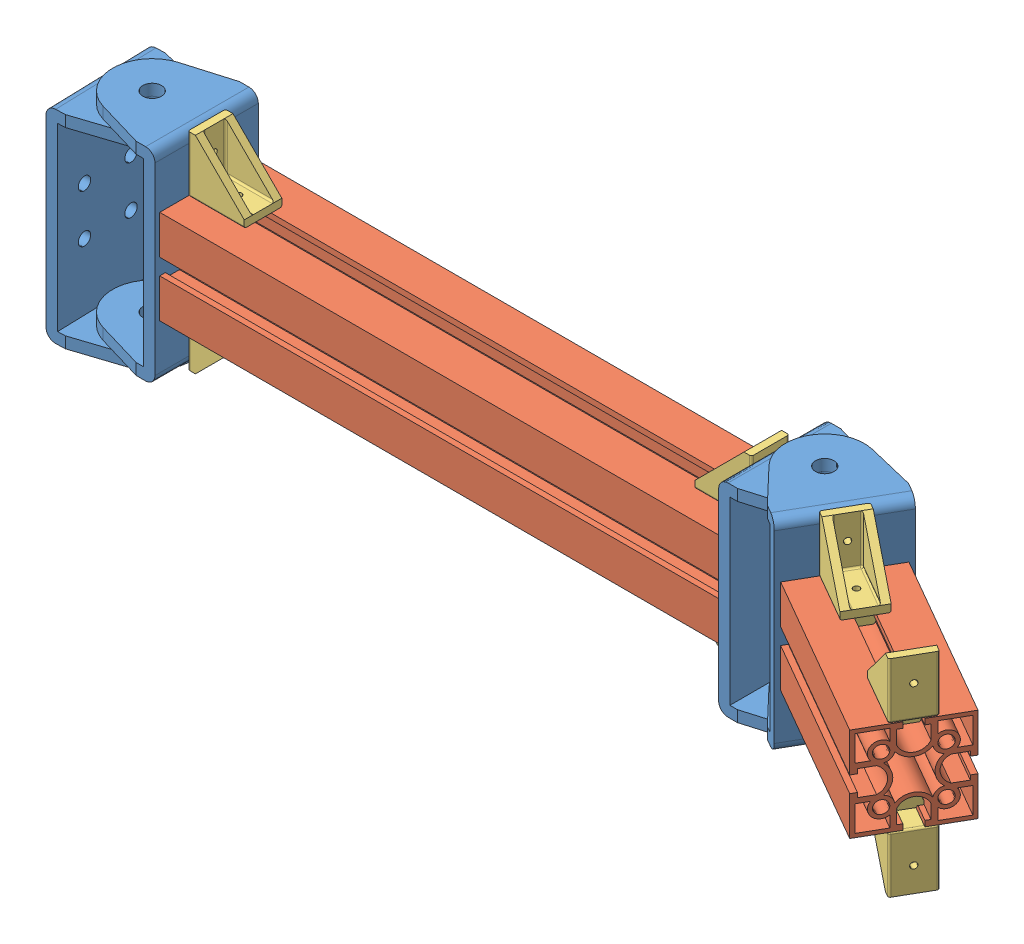
SolidWorks assembly 鋼體小螺絲, configuration 雙掛勾. Lengths in mm.
Overall size (512.05 121 120.35).
22 component instances, 3 part files, 56 mates.
Components (placement in the parent):
- 掛勾-1: 掛勾 [掛勾11(右)] at (18.5266 -14.7392 107.3914) x (0.99958 0 -0.028981) z (0.028981 0 0.99958) size (50 108 55)
- 掛勾-2: 掛勾 [掛勾(鎖鋁擠那邊)] at (-23.4646 -8.7392 108) x (-1 0 0) z (0 0 -1) size (50 108 55)
- 鋁擠型5050-1: 鋁擠型5050 [5050_L300] at (176.5354 -8.7392 108) x (0 0 -1) z (-1 0 0) size (50 50 300)
- 鋁擠-1: 鋁擠 [直角支架] at (26.5354 16.2608 108) x (-1 0 0) z (0 0 -1) size (30 30 20)
- 鋁擠-2: 鋁擠 [直角支架] at (26.5354 -33.7392 108) x (-1 0 0) z (0 0 1) size (30 30 20)
- 鋁擠-3: 鋁擠 [溝槽] at (43.5354 -31.5392 108) x (0 0 1) z (-1 0 0) size (14.45 6.3 14)
- 鋁擠-4: 鋁擠 [溝槽] at (43.5354 12.4608 108) x (0 0 -1) z (1 0 0) size (14.45 6.3 14)
- 掛勾-3: 掛勾 [掛勾10（右）] at (337.3371 -2.7392 97.5203) x (-0.866583 0 -0.499033) z (-0.499033 0 0.866583)
- 掛勾-4: 掛勾 [掛勾11] at (376.5354 -8.7392 108) x (1 0 0) z (0 0 -1)
- 鋁擠-5: 鋁擠 [溝槽] at (309.5354 -31.5392 108) x (0 0 1) z (-1 0 0) size (14.45 6.3 14)
- 鋁擠-6: 鋁擠 [直角支架] at (326.5354 -33.7392 108) x (1 0 0) z (0 0 -1) size (30 30 20)
- 鋁擠-7: 鋁擠 [直角支架] at (326.5354 16.2608 108) size (30 30 20)
- 鋁擠-8: 鋁擠 [溝槽] at (309.5354 14.0608 108) x (0 0 1) z (1 0 0) size (14.45 6.3 14)
- 鋁擠型5050-2: 鋁擠型5050 [5050_L100] at (423.9955 -2.7392 147.4236) x (0.499033 0 -0.866583) z (-0.866583 0 -0.499033)
- 鋁擠-9: 鋁擠 [直角支架] at (380.6663 -27.7392 122.4719) x (-0.866583 0 -0.499033) z (-0.499033 0 0.866583) size (30 30 20)
- 鋁擠-10: 鋁擠 [直角支架] at (380.6663 22.2608 122.4719) x (0 -1 0) z (-0.499033 0 0.866583) size (30 30 20)
- 鋁擠-11: 鋁擠 [溝槽] at (452.5927 -25.5392 163.8917) x (-0.499033 0 0.866583) z (-0.866583 0 -0.499033) size (14.45 6.3 14)
- 鋁擠-12: 鋁擠 [溝槽] at (452.5927 20.0608 163.8917) x (-0.499033 0 0.866583) z (0.866583 0 0.499033) size (14.45 6.3 14)
- 鋁擠-13: 鋁擠 [溝槽] at (395.3982 20.0608 130.9555) x (0.499033 0 -0.866583) z (-0.866583 0 -0.499033) size (14.45 6.3 14)
- 鋁擠-14: 鋁擠 [溝槽] at (395.3982 -25.5392 130.9555) x (-0.499033 0 0.866583) z (-0.866583 0 -0.499033) size (14.45 6.3 14)
- 鋁擠-15: 鋁擠 [直角支架] at (467.3246 -27.7392 172.3752) x (0 1 0) z (-0.499033 0 0.866583) size (30 30 20)
- 鋁擠-16: 鋁擠 [直角支架] at (467.3246 22.2608 172.3752) x (0 -1 0) z (0.499033 0 -0.866583) size (30 30 20)
Mates (geometry in assembly coordinates):
- 同軸心1: concentric aligned: circle of 掛勾-1; circle of 掛勾-2
- 重合/共線/共點11: coincident anti-aligned: plane of 掛勾-2 through (26.5354 40.2608 80.5) normal (1 0 0); plane of 鋁擠型5050-1 through (26.5354 8.8108 108) normal (-1 0 0)
- 寬度3: width anti-aligned: plane of 鋁擠-3 through (36.5354 -31.0392 111.9) normal (0 0 1); plane of 鋁擠-3 through (36.5354 -31.0392 104.1) normal (0 0 -1); plane of 鋁擠型5050-1 through (26.5354 -33.7392 112.3) normal (0 0 -1); plane of 鋁擠型5050-1 through (26.5354 -33.7392 103.7) normal (0 0 1)
- 重合/共線/共點12: coincident anti-aligned: plane of 鋁擠型5050-1 through (26.5354 -30.7392 103.7) normal (0 1 0); plane of 鋁擠-3 through (36.5354 -30.7392 111.9) normal (0 -1 0)
- 同軸心2: concentric aligned: circle of 鋁擠-2; circle of 鋁擠-3
- 重合/共線/共點14: coincident anti-aligned: plane of 鋁擠型5050-1 through (26.5354 -33.7392 112.3) normal (0 -1 0); plane of 鋁擠-2 through (26.5354 -33.7392 118) normal (0 1 0)
- 重合/共線/共點15: coincident anti-aligned: plane of 掛勾-2 through (26.5354 40.2608 80.5) normal (1 0 0); plane of 鋁擠型5050-1 through (26.5354 8.8108 108) normal (-1 0 0)
- 寬度4: width aligned: plane of 鋁擠型5050-1 through (26.5354 -33.7392 103.7) normal (0 -1 0); plane of 鋁擠型5050-1 through (26.5354 16.2608 103.7) normal (0 1 0); plane of 掛勾-2 through (-23.4646 45.2608 80.5) normal (0 1 0); plane of 掛勾-2 through (-23.4646 -62.7392 80.5) normal (0 -1 0)
- 寬度5: width anti-aligned: plane of 鋁擠型5050-1 through (26.5354 -33.7392 83) normal (0 0 -1); plane of 鋁擠型5050-1 through (26.5354 -33.7392 133) normal (0 0 1); plane of 掛勾-2 through (21.5354 -57.7392 80.5) normal (0 0 -1); plane of 掛勾-2 through (21.5354 -57.7392 135.5) normal (0 0 1)
- 重合/共線/共點17: coincident anti-aligned: plane of 掛勾-2 through (26.5354 40.2608 80.5) normal (1 0 0); plane of 鋁擠-2 through (26.5354 -33.7392 118) normal (-1 0 0)
- 寬度6: width aligned: plane of 鋁擠-4 through (50.5354 12.9608 104.1) normal (0 0 -1); plane of 鋁擠-4 through (50.5354 12.9608 111.9) normal (0 0 1); plane of 鋁擠型5050-1 through (26.5354 16.2608 112.3) normal (0 0 -1); plane of 鋁擠型5050-1 through (26.5354 16.2608 103.7) normal (0 0 1)
- 重合/共線/共點18: coincident aligned: plane of 鋁擠型5050-1 through (26.5354 13.2608 112.3) normal (0 -1 0); plane of 鋁擠-4 through (50.5354 13.2608 104.1) normal (0 -1 0)
- 同軸心3: concentric anti-aligned: circle of 鋁擠-1; circle of 鋁擠-4
- 重合/共線/共點20: coincident anti-aligned: plane of 鋁擠型5050-1 through (26.5354 16.2608 112.3) normal (0 1 0); plane of 鋁擠-1 through (26.5354 16.2608 98) normal (0 -1 0)
- 重合/共線/共點21: coincident anti-aligned: plane of 掛勾-2 through (26.5354 40.2608 80.5) normal (1 0 0); plane of 鋁擠-1 through (26.5354 16.2608 98) normal (-1 0 0)
- 重合/共線/共點22: coincident anti-aligned: plane of 鋁擠型5050-1 through (326.5354 8.8108 108) normal (1 0 0); plane of 掛勾-4 through (326.5354 -57.7392 80.5) normal (-1 0 0)
- 寬度7: width anti-aligned: plane of 掛勾-4 through (331.5354 40.2608 135.5) normal (0 0 1); plane of 掛勾-4 through (331.5354 40.2608 80.5) normal (0 0 -1); plane of 鋁擠型5050-1 through (26.5354 16.2608 83) normal (0 0 -1); plane of 鋁擠型5050-1 through (26.5354 -33.7392 133) normal (0 0 1)
- 寬度8: width anti-aligned: plane of 掛勾-4 through (376.5354 -62.7392 80.5) normal (0 -1 0); plane of 掛勾-4 through (376.5354 45.2608 80.5) normal (0 1 0); plane of 鋁擠型5050-1 through (26.5354 16.2608 103.7) normal (0 1 0); plane of 鋁擠型5050-1 through (26.5354 -33.7392 103.7) normal (0 -1 0)
- 重合/共線/共點24: coincident anti-aligned: plane of 鋁擠型5050-1 through (26.5354 -30.7392 103.7) normal (0 1 0); plane of 鋁擠-5 through (302.5354 -30.7392 104.1) normal (0 -1 0)
- 寬度10: width aligned: plane of 鋁擠型5050-1 through (26.5354 -33.7392 103.7) normal (0 0 1); plane of 鋁擠型5050-1 through (26.5354 -33.7392 112.3) normal (0 0 -1); plane of 鋁擠-5 through (302.5354 -31.0392 111.9) normal (0 0 1); plane of 鋁擠-5 through (302.5354 -31.0392 104.1) normal (0 0 -1)
- 重合/共線/共點25: coincident anti-aligned: plane of 鋁擠型5050-1 through (26.5354 13.2608 103.7) normal (0 -1 0); plane of 鋁擠-8 through (316.5354 13.2608 104.1) normal (0 1 0)
- 寬度11: width anti-aligned: plane of 鋁擠型5050-1 through (26.5354 16.2608 103.7) normal (0 0 1); plane of 鋁擠型5050-1 through (26.5354 16.2608 112.3) normal (0 0 -1); plane of 鋁擠-8 through (316.5354 13.5608 104.1) normal (0 0 -1); plane of 鋁擠-8 through (316.5354 13.5608 111.9) normal (0 0 1)
- 重合/共線/共點26: coincident aligned: circle of 鋁擠-7; cylinder of 鋁擠-8 through (309.5354 14.0608 108) axis (0 1 0) radius 1.65
- 重合/共線/共點27: coincident anti-aligned: plane of 鋁擠型5050-1 through (26.5354 16.2608 103.7) normal (0 1 0); plane of 鋁擠-7 through (326.5354 16.2608 118) normal (0 -1 0)
- 同軸心4: concentric aligned: cylinder of 掛勾-4 through (376.5364 33.2608 108) axis (-1 0 0) radius 1.5; cylinder of 鋁擠-7 through (322.5354 33.2608 108) axis (-1 0 0) radius 1.65
- 重合/共線/共點29: coincident anti-aligned: plane of 掛勾-4 through (326.5354 -57.7392 80.5) normal (-1 0 0); plane of 鋁擠-7 through (326.5354 16.2608 118) normal (1 0 0)
- 同軸心7: concentric aligned: circle of 鋁擠-5; circle of 鋁擠-6
- 重合/共線/共點33: coincident anti-aligned: plane of 鋁擠型5050-1 through (26.5354 -33.7392 112.3) normal (0 -1 0); plane of 鋁擠-6 through (326.5354 -33.7392 98) normal (0 1 0)
- 同軸心8: concentric aligned: cylinder of 掛勾-4 through (376.5364 -50.7392 108) axis (-1 0 0) radius 1.5; cylinder of 鋁擠-6 through (322.5354 -50.7392 108) axis (-1 0 0) radius 1.65
- 重合/共線/共點34: coincident anti-aligned: plane of 掛勾-4 through (326.5354 -57.7392 80.5) normal (-1 0 0); plane of 鋁擠-6 through (326.5354 -33.7392 98) normal (1 0 0)
- 同軸心9: concentric aligned: cylinder of 掛勾-3 through (355.5354 67.2608 108) axis (0 -1 0) radius 5; cylinder of 掛勾-4 through (355.5354 60.8171 108) axis (0 -1 0) radius 5.5
- 重合/共線/共點35: coincident anti-aligned: plane of 掛勾-4 through (376.5354 -56.7392 80.5) normal (0 1 0); plane of 掛勾-3 through (323.6137 -56.7392 121.3514) normal (0 -1 0)
- 重合/共線/共點36: coincident anti-aligned: plane of 掛勾-1 through (19.3235 39.2608 134.8798) normal (0 1 0); plane of 掛勾-2 through (-23.4646 39.2608 80.5) normal (0 -1 0)
- 同軸心10: concentric aligned: circle of 掛勾-3; cylinder of 鋁擠型5050-2 through (374.3036 -27.4892 133.5209) axis (0.866583 0 0.499033) radius 3.4
- 重合/共線/共點38: coincident anti-aligned: plane of 掛勾-3 through (366.9429 -63.7392 146.303) normal (0.866583 0 0.499033); plane of 鋁擠型5050-2 through (380.6663 2.8108 122.4719) normal (-0.866583 0 -0.499033)
- 同軸心11: concentric aligned: cylinder of 掛勾-3 through (378.3631 -1.9892 106.4327) axis (0.866583 0 0.499033) radius 3.4; cylinder of 鋁擠型5050-2 through (387.029 -1.9892 111.423) axis (0.866583 0 0.499033) radius 3.4
- 重合/共線/共點39: coincident anti-aligned: plane of 鋁擠型5050-2 through (378.5205 -36.7392 126.1983) normal (0 1 0); plane of 鋁擠-11 through (448.4728 -36.7392 157.0188) normal (0 -1 0)
- 重合/共線/共點40: coincident anti-aligned: plane of 鋁擠型5050-2 through (378.5205 7.2608 126.1983) normal (0 -1 0); plane of 鋁擠-12 through (456.7126 7.2608 170.7646) normal (0 1 0)
- 重合/共線/共點41: coincident anti-aligned: plane of 鋁擠型5050-2 through (378.5205 -36.7392 126.1983) normal (0 1 0); plane of 鋁擠-14 through (387.3859 -36.7392 130.8419) normal (0 -1 0)
- 寬度12: width aligned: plane of 鋁擠型5050-2 through (378.5205 -39.7392 126.1983) normal (0.499033 0 -0.866583); plane of 鋁擠型5050-2 through (382.8121 -39.7392 118.7456) normal (-0.499033 0 0.866583); plane of 鋁擠-14 through (391.2784 -37.0392 124.0826) normal (0.499033 0 -0.866583); plane of 鋁擠-14 through (387.3859 -37.0392 130.8419) normal (-0.499033 0 0.866583)
- 寬度13: width anti-aligned: plane of 鋁擠型5050-2 through (382.8121 -39.7392 118.7456) normal (-0.499033 0 0.866583); plane of 鋁擠型5050-2 through (378.5205 -39.7392 126.1983) normal (0.499033 0 -0.866583); plane of 鋁擠-11 through (448.4728 -37.0392 157.0188) normal (0.499033 0 -0.866583); plane of 鋁擠-11 through (444.5804 -37.0392 163.7781) normal (-0.499033 0 0.866583)
- 寬度14: width anti-aligned: plane of 鋁擠型5050-2 through (382.8121 10.2608 118.7456) normal (-0.499033 0 0.866583); plane of 鋁擠型5050-2 through (378.5205 10.2608 126.1983) normal (0.499033 0 -0.866583); plane of 鋁擠-13 through (391.2784 7.5608 124.0826) normal (0.499033 0 -0.866583); plane of 鋁擠-13 through (387.3859 7.5608 130.8419) normal (-0.499033 0 0.866583)
- 重合/共線/共點43: coincident anti-aligned: plane of 鋁擠型5050-2 through (378.5205 7.2608 126.1983) normal (0 -1 0); plane of 鋁擠-13 through (387.3859 7.2608 130.8419) normal (0 1 0)
- 寬度15: width anti-aligned: plane of 鋁擠型5050-2 through (378.5205 10.2608 126.1983) normal (0.499033 0 -0.866583); plane of 鋁擠型5050-2 through (382.8121 10.2608 118.7456) normal (-0.499033 0 0.866583); plane of 鋁擠-12 through (456.7126 7.5608 170.7646) normal (-0.499033 0 0.866583); plane of 鋁擠-12 through (460.605 7.5608 164.0052) normal (0.499033 0 -0.866583)
- 同軸心12: concentric aligned: circle of 鋁擠-9; cylinder of 鋁擠-14 through (395.3982 -37.5392 130.9555) axis (0 -1 0) radius 1.65
- 同軸心13: concentric aligned: circle of 掛勾-3; circle of 鋁擠-9
- 重合/共線/共點44: coincident anti-aligned: plane of 掛勾-3 through (366.9429 -63.7392 146.303) normal (0.866583 0 0.499033); plane of 鋁擠-9 through (375.676 -39.7392 131.1378) normal (-0.866583 0 -0.499033)
- 同軸心14: concentric aligned: circle of 鋁擠-10; circle of 鋁擠-13
- 同軸心15: concentric aligned: circle of 掛勾-3; circle of 鋁擠-10
- 重合/共線/共點45: coincident anti-aligned: plane of 掛勾-3 through (366.9429 -63.7392 146.303) normal (0.866583 0 0.499033); plane of 鋁擠-10 through (375.676 10.2608 131.1378) normal (-0.866583 0 -0.499033)
- 同軸心16: concentric aligned: circle of 鋁擠-11; circle of 鋁擠-15
- 重合/共線/共點48: coincident anti-aligned: plane of 鋁擠型5050-2 through (382.8121 -39.7392 118.7456) normal (0 -1 0); plane of 鋁擠-15 through (462.3343 -39.7392 181.041) normal (0 1 0)
- 重合/共線/共點49: coincident aligned: plane of 鋁擠型5050-2 through (467.3246 2.8108 172.3752) normal (0.866583 0 0.499033); plane of 鋁擠-15 through (462.3343 -39.7392 181.041) normal (0.866583 0 0.499033)
- 同軸心17: concentric aligned: circle of 鋁擠-12; circle of 鋁擠-16
- 重合/共線/共點52: coincident anti-aligned: plane of 鋁擠型5050-2 through (382.8121 10.2608 118.7456) normal (0 1 0); plane of 鋁擠-16 through (472.3149 10.2608 163.7094) normal (0 -1 0)
- 重合/共線/共點53: coincident aligned: plane of 鋁擠型5050-2 through (467.3246 2.8108 172.3752) normal (0.866583 0 0.499033); plane of 鋁擠-16 through (472.3149 10.2608 163.7094) normal (0.866583 0 0.499033)
